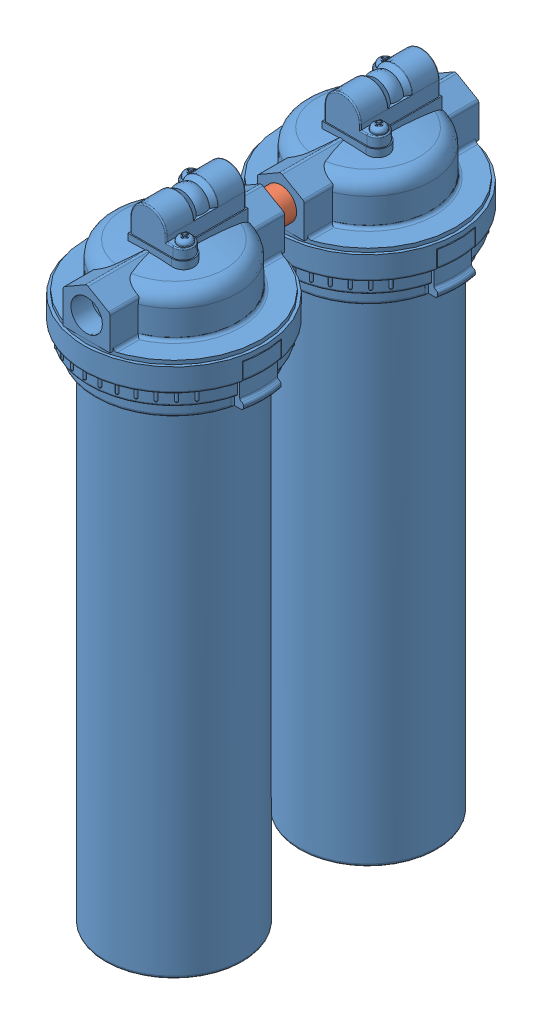
SolidWorks assembly ReadingTech_4P-090-M04-DCi, configuration Default. Lengths in mm.
Overall size (121.86 451.22 252.73).
3 component instances, 2 part files, 3 mates.
Components (placement in the parent):
- ReadingTech_3P090M04Fi-1: ReadingTech_3P090M04Fi [Default] at (-54.8736 -196.0444 24.5231) size (121.86 451.22 121.67)
- ReadingTech_3P090M04Fi-2: ReadingTech_3P090M04Fi [Default] at (-54.8736 -196.0444 155.5871) size (121.86 451.22 121.67)
- ReadingTech- 90,150cfm_connector_.5in-1: ReadingTech- 90,150cfm_connector_.5in [Default] at (-54.8736 188.8926 96.6591) x (1 0 0) z (0 1 0) size (21.34 13.21 21.34)
Mates (geometry in assembly coordinates):
- Coincident1: coincident anti-aligned: circle of ReadingTech_3P090M04Fi-1; circle of ReadingTech- 90,150cfm_connector_.5in-1
- Coincident2: coincident aligned: circle of ReadingTech_3P090M04Fi-2; circle of ReadingTech- 90,150cfm_connector_.5in-1
- Coincident3: coincident aligned: plane of ReadingTech_3P090M04Fi-1 through (-39.0621 197.6556 83.4511) normal (1 0 0); plane of ReadingTech_3P090M04Fi-2 through (-39.0621 197.6556 214.5151) normal (1 0 0)
